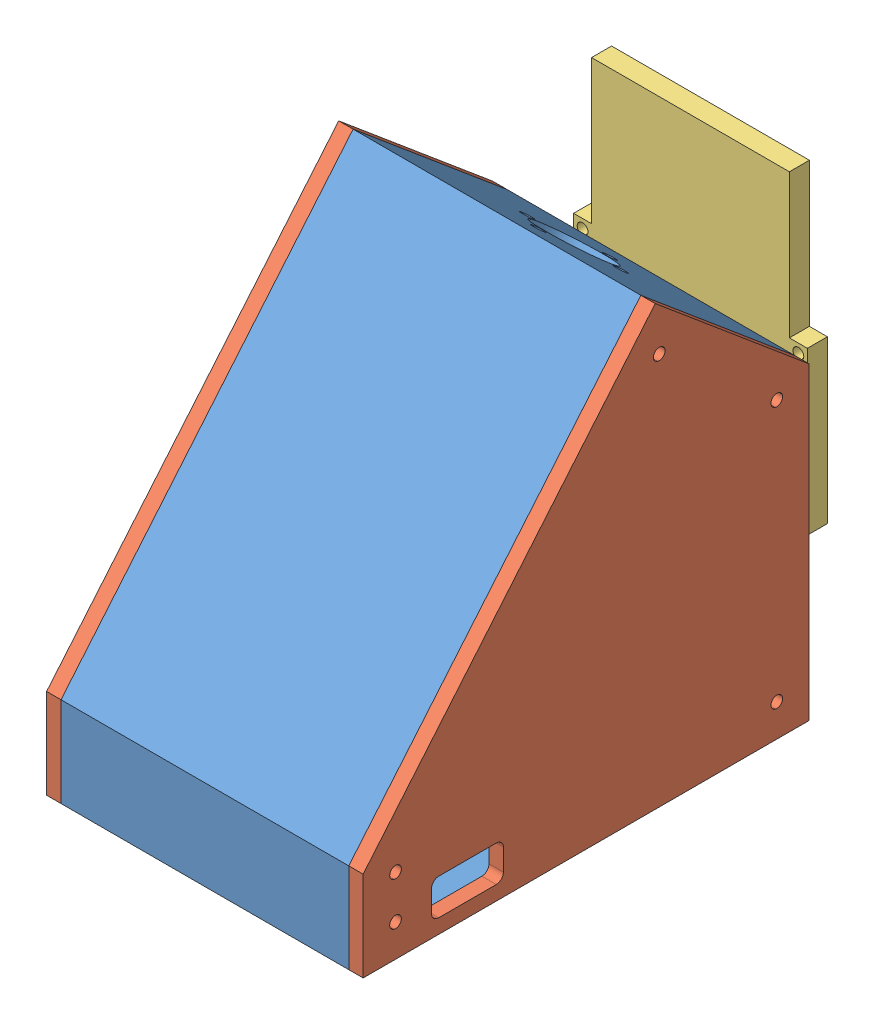
SolidWorks assembly Assem1, configuration Default. Lengths in mm.
Overall size (88 121.77 140.56).
4 component instances, 3 part files, 8 mates.
Components (placement in the parent):
- confetti_holder1-1: confetti_holder1 [Default] at (34.2989 23.9706 32.5353) size (80 121.77 124)
- confetti_holder2-1: confetti_holder2 [Default] at (74.2989 23.9706 32.5353) x (0 0 -1) z (1 0 0) size (124 121.77 4)
- confetti_holder2-2: confetti_holder2 [Default] at (-9.7011 23.9706 32.5353) x (0 0 -1) z (1 0 0) size (124 121.77 4)
- cyclyinder_offset-1: cyclyinder_offset [Default] at (34.2989 75.8358 11.9709) x (1 0 0) z (0 -1 0) size (65 5.56 85)
Mates (geometry in assembly coordinates):
- Concentric1: concentric aligned: circle of confetti_holder1-1; circle of confetti_holder2-1
- Coincident1: coincident aligned: plane of confetti_holder1-1 through (74.2989 91.7352 113.294) normal (0 0.642788 0.766044); plane of confetti_holder2-1 through (78.2989 91.7352 113.294) normal (0 0.642788 0.766044)
- Coincident2: coincident anti-aligned: plane of confetti_holder1-1 through (74.2989 23.9706 32.5353) normal (1 0 0); plane of confetti_holder2-1 through (74.2989 23.9706 32.5353) normal (-1 0 0)
- Concentric2: concentric aligned: circle of confetti_holder1-1; circle of confetti_holder2-2
- Parallel1: parallel aligned: plane of confetti_holder2-2 through (-5.7011 91.7352 113.294) normal (0 0.642788 0.766044); plane of confetti_holder1-1 through (74.2989 91.7352 113.294) normal (0 0.642788 0.766044)
- Coincident4: coincident anti-aligned: plane of confetti_holder1-1 through (-5.7011 23.9706 32.5353) normal (-1 0 0); plane of confetti_holder2-2 through (-5.7011 23.9706 32.5353) normal (1 0 0)
- Concentric3: concentric anti-aligned: circle of confetti_holder1-1; circle of cyclyinder_offset-1
- Parallel2: parallel aligned: plane of confetti_holder1-1 through (74.2989 19.9706 32.5353) normal (0 -1 0); plane of cyclyinder_offset-1 through (34.2989 53.3358 17.5309) normal (0 -1 0)
